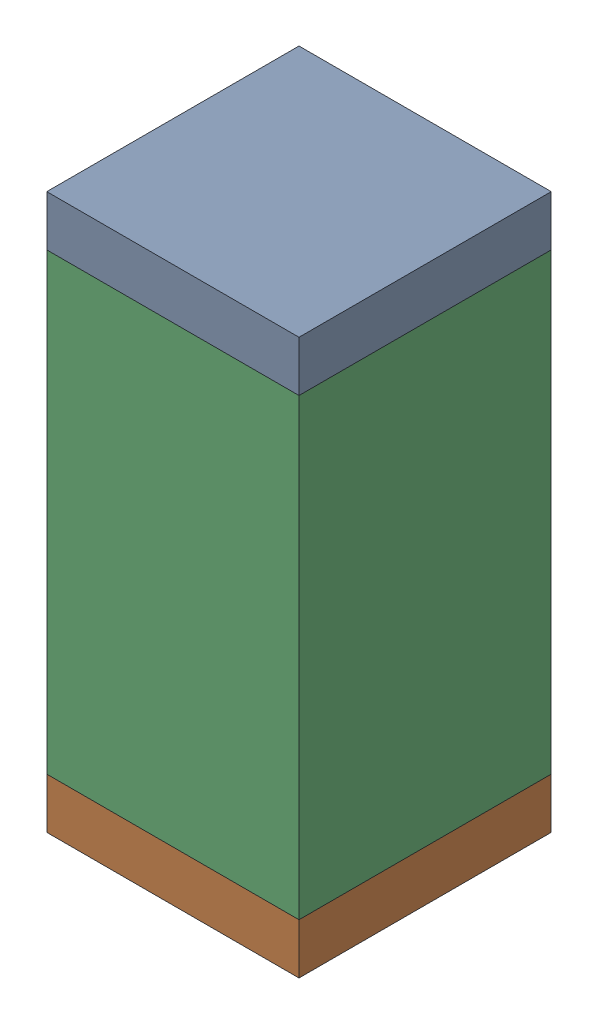
SolidWorks assembly C120, configuration Default. Lengths in mm.
Overall size (0.5 1.1 0.5).
6 component instances, 2 part files, 0 mates.
Components (placement in the parent):
- 810157360-1: 810157360 [Default] at (131.35 20.5 0) size (0.5 0.1 0.5)
  - Extruded_9-1: Extruded_9 [Default] at origin size (0.5 0.1 0.5)
- 810157360-2: 810157360 [Default] at (131.35 19.5 0) size (0.5 0.1 0.5)
  - Extruded_9-1: Extruded_9 [Default] at origin size (0.5 0.1 0.5)
- 791586336-1: 791586336 [Default] at (131.35 20 0) size (0.5 0.9 0.5)
  - Extruded_8-1: Extruded_8 [Default] at origin size (0.5 0.9 0.5)
